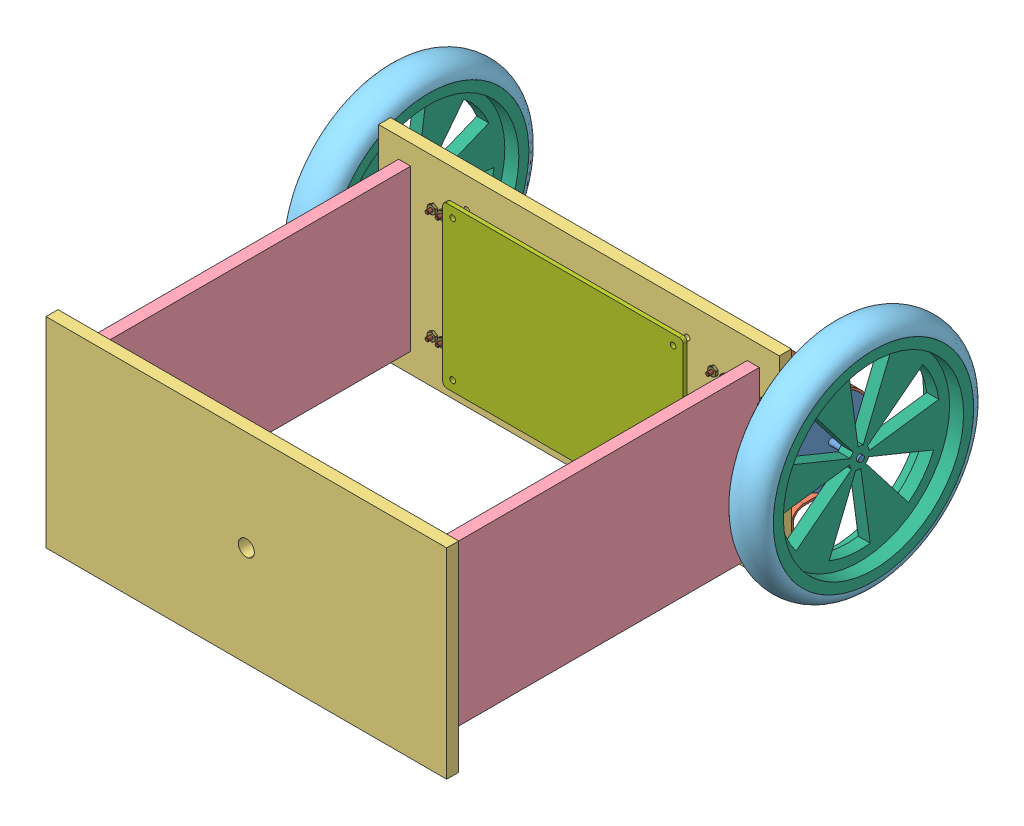
SolidWorks assembly marvin1, configuration Défaut. Lengths in mm.
Overall size (242 114 249).
83 component instances, 12 part files, 144 mates.
Components (placement in the parent):
- moteur-fixation-1: moteur-fixation [Défaut] at (-12.3329 9.7306 0.5) size (75 60.01 41)
  - moteur40-60-1: moteur40-60 [Défaut] at (-38.9333 4.3561 110) size (75 40 40)
  - fixationMoteur40-2-2: fixationMoteur40-2 [Défaut] at (21.0667 4.3561 110) x (0 1 0) z (0 0 1) size (60.01 10 41)
  - fixationMoteur40-2-3: fixationMoteur40-2 [Défaut] at (-3.9333 4.3561 110) x (0 1 0) z (0 0 1) size (60.01 10 41)
  - fixationMoteur40-2-4: fixationMoteur40-2 [Défaut] at (-28.9333 4.3561 110) x (0 1 0) z (0 0 1) size (60.01 10 41)
- plaque200-100-6-1: plaque200-100-6 [Défaut] at (-151.2662 -35.9099 130.5) x (0 0 1) z (0 1 0) size (6 200 100)
- moteur-fixation-2: moteur-fixation [Défaut] at (-170.1995 18.4428 0.5) x (-1 0 0) z (0 0 1) size (75 60.01 41)
  - moteur40-60-1: moteur40-60 [Défaut] at (-38.9333 4.3561 110) size (75 40 40)
  - fixationMoteur40-2-2: fixationMoteur40-2 [Défaut] at (21.0667 4.3561 110) x (0 1 0) z (0 0 1) size (60.01 10 41)
  - fixationMoteur40-2-3: fixationMoteur40-2 [Défaut] at (-3.9333 4.3561 110) x (0 1 0) z (0 0 1) size (60.01 10 41)
  - fixationMoteur40-2-4: fixationMoteur40-2 [Défaut] at (-28.9333 4.3561 110) x (0 1 0) z (0 0 1) size (60.01 10 41)
- plaque160-80-6-1: plaque160-80-6 [Défaut] at (-7.2662 -25.9099 296.5) x (1 0 0) z (0 1 0) size (6 160 80)
- roue200-2-1: roue200-2 [Défaut] at (133.7338 9.4583 108.5273) x (0 0 1) z (-1 0 0) size (114 114 20)
  - pneu-200-2-1: pneu-200-2 [Défaut] at (1.9727 4.6283 114) size (114 114 20)
  - jante10-2-1: jante10-2 [Défaut] at (1.9727 4.6283 104) size (100 100 20)
- roue200-2-2: roue200-2 [Défaut] at (-316.2662 9.4583 112.4727) x (0 0 -1) z (1 0 0) size (114 114 20)
  - pneu-200-2-1: pneu-200-2 [Défaut] at (1.9727 4.6283 114) size (114 114 20)
  - jante10-2-1: jante10-2 [Défaut] at (1.9727 4.6283 104) size (100 100 20)
- plaque160-80-6-2: plaque160-80-6 [Défaut] at (-181.2662 -25.9099 296.5) x (1 0 0) z (0 1 0) size (6 160 80)
- plaque200-100-6-2: plaque200-100-6 [Défaut] at (-31.2662 64.0901 296.5) x (0 0 1) z (0 -1 0) size (6 200 100)
- carte-1: carte [Défaut] at (-152.2662 -25.9099 141.5) size (120 80 2)
- butee15-15-1: butee15-15 [Défaut] at (-51.2662 9.0901 130.5) x (0 0 -1) z (0 1 0) size (16 16 10)
- butee15-15-2: butee15-15 [Défaut] at (-131.2662 19.0901 130.5) x (0 0 -1) z (0 -1 0) size (16 16 10)
- socket head cap screw_am-1: socket head cap screw_am [B18.3.1M - 2 x 0.4 x 10 Hex SHCS -- 10NHX] at (-125.7318 11.5901 128.5) x (0 0 1) z (-1 0 0) size (12 3.8 3.8)
- socket head cap screw_am-2: socket head cap screw_am [B18.3.1M - 2 x 0.4 x 10 Hex SHCS -- 10NHX] at (-125.7318 16.5901 128.5) x (0 0 1) z (-1 0 0) size (12 3.8 3.8)
- socket head cap screw_am-3: socket head cap screw_am [B18.3.1M - 2 x 0.4 x 10 Hex SHCS -- 10NHX] at (-118.7318 11.5901 128.5) x (0 0 1) z (-1 0 0) size (12 3.8 3.8)
- socket head cap screw_am-4: socket head cap screw_am [B18.3.1M - 2 x 0.4 x 10 Hex SHCS -- 10NHX] at (-118.7318 16.5901 128.5) x (0 0 1) z (-1 0 0) size (12 3.8 3.8)
- hex nut style 1_am-1: hex nut style 1_am [B18.2.4.1M - Hex nut, Style 1,  M2 x 0.4 --D-N] at (-125.7318 11.5901 138.1) size (4 4.62 1.6)
- hex nut style 1_am-2: hex nut style 1_am [B18.2.4.1M - Hex nut, Style 1,  M2 x 0.4 --D-N] at (-118.7318 11.5901 138.1) size (4 4.62 1.6)
- hex nut style 1_am-3: hex nut style 1_am [B18.2.4.1M - Hex nut, Style 1,  M2 x 0.4 --D-N] at (-118.7318 16.5901 138.1) size (4 4.62 1.6)
- hex nut style 1_am-4: hex nut style 1_am [B18.2.4.1M - Hex nut, Style 1,  M2 x 0.4 --D-N] at (-125.7318 16.5901 138.1) size (4 4.62 1.6)
- socket head cap screw_am-5: socket head cap screw_am [B18.3.1M - 2 x 0.4 x 10 Hex SHCS -- 10NHX] at (-63.8006 16.5901 128.5) x (0 0 1) z (-1 0 0) size (12 3.8 3.8)
- socket head cap screw_am-6: socket head cap screw_am [B18.3.1M - 2 x 0.4 x 10 Hex SHCS -- 10NHX] at (-56.8006 16.5901 128.5) x (0 0 1) z (-1 0 0) size (12 3.8 3.8)
- socket head cap screw_am-7: socket head cap screw_am [B18.3.1M - 2 x 0.4 x 10 Hex SHCS -- 10NHX] at (-56.8006 11.6838 128.5) x (0 0 1) z (-1 0 0) size (12 3.8 3.8)
- socket head cap screw_am-8: socket head cap screw_am [B18.3.1M - 2 x 0.4 x 10 Hex SHCS -- 10NHX] at (-63.8006 11.5901 128.5) x (0 0 1) z (-1 0 0) size (12 3.8 3.8)
- hex nut style 1_am-5: hex nut style 1_am [B18.2.4.1M - Hex nut, Style 1,  M2 x 0.4 --D-N] at (-63.8006 16.5901 138.1) size (4 4.62 1.6)
- hex nut style 1_am-6: hex nut style 1_am [B18.2.4.1M - Hex nut, Style 1,  M2 x 0.4 --D-N] at (-56.8006 16.5901 138.1) size (4 4.62 1.6)
- hex nut style 1_am-7: hex nut style 1_am [B18.2.4.1M - Hex nut, Style 1,  M2 x 0.4 --D-N] at (-56.8006 11.6838 138.1) size (4 4.62 1.6)
- hex nut style 1_am-8: hex nut style 1_am [B18.2.4.1M - Hex nut, Style 1,  M2 x 0.4 --D-N] at (-63.8006 11.5901 138.1) size (4 4.62 1.6)
- socket head cap screw_ai-3: socket head cap screw_ai [HX-SHCS 0.073-72x0.375x0.375-N] at (-23.7662 -13.4168 128.6458) x (0 0 1) z (-1 0 0) size (11.38 3 3)
- socket head cap screw_ai-4: socket head cap screw_ai [HX-SHCS 0.073-72x0.375x0.375-N] at (-18.7662 -13.4168 128.6458) x (0 0 1) z (-1 0 0) size (11.38 3 3)
- socket head cap screw_ai-5: socket head cap screw_ai [HX-SHCS 0.073-72x0.375x0.375-N] at (1.2338 -13.4168 128.6458) x (0 0 1) z (-1 0 0) size (11.38 3 3)
- socket head cap screw_ai-6: socket head cap screw_ai [HX-SHCS 0.073-72x0.375x0.375-N] at (6.2338 -13.4168 128.6458) x (0 0 1) z (-1 0 0) size (11.38 3 3)
- socket head cap screw_ai-7: socket head cap screw_ai [HX-SHCS 0.073-72x0.375x0.375-N] at (6.9751 40.8664 128.6458) x (0 0 1) z (-1 0 0) size (11.38 3 3)
- socket head cap screw_ai-8: socket head cap screw_ai [HX-SHCS 0.073-72x0.375x0.375-N] at (1.9751 40.8664 128.6458) x (0 0 1) z (-1 0 0) size (11.38 3 3)
- socket head cap screw_ai-9: socket head cap screw_ai [HX-SHCS 0.073-72x0.375x0.375-N] at (-17.8435 41.1189 128.6458) x (0 0 1) z (-1 0 0) size (11.38 3 3)
- socket head cap screw_ai-10: socket head cap screw_ai [HX-SHCS 0.073-72x0.375x0.375-N] at (-23.7662 41.5901 128.6458) x (0 0 1) z (-1 0 0) size (11.38 3 3)
- socket head cap screw_ai-11: socket head cap screw_ai [HX-SHCS 0.073-72x0.375x0.375-N] at (-42.8435 41.1189 128.6458) x (0 0 1) z (-1 0 0) size (11.38 3 3)
- socket head cap screw_ai-12: socket head cap screw_ai [HX-SHCS 0.073-72x0.375x0.375-N] at (-47.7301 41.5901 128.6458) x (0 0 1) z (-1 0 0) size (11.38 3 3)
- socket head cap screw_ai-13: socket head cap screw_ai [HX-SHCS 0.073-72x0.375x0.375-N] at (-132.8435 41.1189 128.6458) x (0 0 1) z (-1 0 0) size (11.38 3 3)
- socket head cap screw_ai-14: socket head cap screw_ai [HX-SHCS 0.073-72x0.375x0.375-N] at (-137.8435 41.1189 128.6458) x (0 0 1) z (-1 0 0) size (11.38 3 3)
- socket head cap screw_ai-15: socket head cap screw_ai [HX-SHCS 0.073-72x0.375x0.375-N] at (-158.7662 41.5901 128.6458) x (0 0 1) z (-1 0 0) size (11.38 3 3)
- socket head cap screw_ai-16: socket head cap screw_ai [HX-SHCS 0.073-72x0.375x0.375-N] at (-163.7662 41.5901 128.6458) x (0 0 1) z (-1 0 0) size (11.38 3 3)
- socket head cap screw_ai-17: socket head cap screw_ai [HX-SHCS 0.073-72x0.375x0.375-N] at (-183.7662 41.5901 128.6458) x (0 0 1) z (-1 0 0) size (11.38 3 3)
- socket head cap screw_ai-18: socket head cap screw_ai [HX-SHCS 0.073-72x0.375x0.375-N] at (-188.7662 41.5901 128.6458) x (0 0 1) z (-1 0 0) size (11.38 3 3)
- socket head cap screw_ai-19: socket head cap screw_ai [HX-SHCS 0.073-72x0.375x0.375-N] at (-188.7662 -13.4168 128.6458) x (0 0 1) z (-1 0 0) size (11.38 3 3)
- socket head cap screw_ai-20: socket head cap screw_ai [HX-SHCS 0.073-72x0.375x0.375-N] at (-183.7662 -13.4168 128.6458) x (0 0 1) z (-1 0 0) size (11.38 3 3)
- socket head cap screw_ai-21: socket head cap screw_ai [HX-SHCS 0.073-72x0.375x0.375-N] at (-163.7662 -13.4168 128.6458) x (0 0 1) z (-1 0 0) size (11.38 3 3)
- socket head cap screw_ai-22: socket head cap screw_ai [HX-SHCS 0.073-72x0.375x0.375-N] at (-158.7662 -13.4168 128.6458) x (0 0 1) z (-1 0 0) size (11.38 3 3)
- socket head cap screw_ai-23: socket head cap screw_ai [HX-SHCS 0.073-72x0.375x0.375-N] at (-138.7662 -13.4168 128.6458) x (0 0 1) z (-1 0 0) size (11.38 3 3)
- socket head cap screw_ai-24: socket head cap screw_ai [HX-SHCS 0.073-72x0.375x0.375-N] at (-133.7662 -13.4168 128.6458) x (0 0 1) z (-1 0 0) size (11.38 3 3)
- machine screw nut hex_ai-1: machine screw nut hex_ai [MSHXNUT 0.073-72-S-N] at (-23.7662 -13.4168 137.77) size (3.96 4.58 1.27)
- machine screw nut hex_ai-2: machine screw nut hex_ai [MSHXNUT 0.073-72-S-N] at (-18.7662 -13.4168 137.77) size (3.96 4.58 1.27)
- machine screw nut hex_ai-3: machine screw nut hex_ai [MSHXNUT 0.073-72-S-N] at (1.2338 -13.4168 137.77) size (3.96 4.58 1.27)
- machine screw nut hex_ai-4: machine screw nut hex_ai [MSHXNUT 0.073-72-S-N] at (6.2338 -13.4168 137.77) size (3.96 4.58 1.27)
- machine screw nut hex_ai-5: machine screw nut hex_ai [MSHXNUT 0.073-72-S-N] at (6.9751 40.8664 137.77) size (3.96 4.58 1.27)
- machine screw nut hex_ai-6: machine screw nut hex_ai [MSHXNUT 0.073-72-S-N] at (1.9751 40.8664 137.77) size (3.96 4.58 1.27)
- machine screw nut hex_ai-7: machine screw nut hex_ai [MSHXNUT 0.073-72-S-N] at (-17.8435 41.1189 137.77) size (3.96 4.58 1.27)
- machine screw nut hex_ai-8: machine screw nut hex_ai [MSHXNUT 0.073-72-S-N] at (-23.7662 41.5901 137.77) size (3.96 4.58 1.27)
- machine screw nut hex_ai-9: machine screw nut hex_ai [MSHXNUT 0.073-72-S-N] at (-42.8435 41.1189 137.77) size (3.96 4.58 1.27)
- machine screw nut hex_ai-10: machine screw nut hex_ai [MSHXNUT 0.073-72-S-N] at (-47.7301 41.5901 137.77) size (3.96 4.58 1.27)
- machine screw nut hex_ai-11: machine screw nut hex_ai [MSHXNUT 0.073-72-S-N] at (-132.8435 41.1189 137.77) size (3.96 4.58 1.27)
- machine screw nut hex_ai-12: machine screw nut hex_ai [MSHXNUT 0.073-72-S-N] at (-137.8435 41.1189 137.77) size (3.96 4.58 1.27)
- machine screw nut hex_ai-13: machine screw nut hex_ai [MSHXNUT 0.073-72-S-N] at (-158.7662 41.5901 137.77) size (3.96 4.58 1.27)
- machine screw nut hex_ai-14: machine screw nut hex_ai [MSHXNUT 0.073-72-S-N] at (-163.7662 41.5901 137.77) size (3.96 4.58 1.27)
- machine screw nut hex_ai-15: machine screw nut hex_ai [MSHXNUT 0.073-72-S-N] at (-183.7662 41.5901 137.77) size (3.96 4.58 1.27)
- machine screw nut hex_ai-16: machine screw nut hex_ai [MSHXNUT 0.073-72-S-N] at (-188.7662 41.5901 137.77) size (3.96 4.58 1.27)
- machine screw nut hex_ai-17: machine screw nut hex_ai [MSHXNUT 0.073-72-S-N] at (-188.7662 -13.4168 137.77) size (3.96 4.58 1.27)
- machine screw nut hex_ai-18: machine screw nut hex_ai [MSHXNUT 0.073-72-S-N] at (-183.7662 -13.4168 137.77) size (3.96 4.58 1.27)
- machine screw nut hex_ai-19: machine screw nut hex_ai [MSHXNUT 0.073-72-S-N] at (-163.7662 -13.4168 137.77) size (3.96 4.58 1.27)
- machine screw nut hex_ai-20: machine screw nut hex_ai [MSHXNUT 0.073-72-S-N] at (-158.7662 -13.4168 137.77) size (3.96 4.58 1.27)
- machine screw nut hex_ai-21: machine screw nut hex_ai [MSHXNUT 0.073-72-S-N] at (-138.7662 -13.4168 137.77) size (3.96 4.58 1.27)
- machine screw nut hex_ai-22: machine screw nut hex_ai [MSHXNUT 0.073-72-S-N] at (-133.7662 -13.4168 137.77) size (3.96 4.58 1.27)
Mates (geometry in assembly coordinates):
- Coïncidente1: coincident: plane of moteur-fixation-1/fixationMoteur40-2-2 through (-1.2662 39.0501 130.5) normal (0 0 1); plane of plaque200-100-6-1 through (8.7338 64.0901 130.5) normal (0 0 -1)
- Coïncidente2: coincident: plane of moteur-fixation-1/fixationMoteur40-2-2 through (8.7338 -12.303 124.2714) normal (1 0 0); plane of plaque200-100-6-1 through (8.7338 64.0901 130.5) normal (1 0 0)
- Distance1: distance = 20 mm: plane of moteur-fixation-1/fixationMoteur40-2-2 through (-1.2662 44.0901 130.5) normal (0 1 0); plane of plaque200-100-6-1 through (-151.2662 64.0901 130.5) normal (0 1 0)
- Coïncidente4: coincident: plane of plaque200-100-6-1 through (-191.2662 64.0901 130.5) normal (-1 0 0); plane of moteur-fixation-2/moteur40-60-1 through (-191.2662 14.0867 110.5) normal (-1 0 0)
- Coïncidente5: coincident: plane of plaque200-100-6-1 through (8.7338 64.0901 130.5) normal (0 0 -1); plane of moteur-fixation-2/fixationMoteur40-2-2 through (-181.2662 39.0501 130.5) normal (0 0 1)
- Distance2: distance = 20 mm: plane of moteur-fixation-2/fixationMoteur40-2-2 through (-181.2662 44.0901 130.5) normal (0 1 0); plane of plaque200-100-6-1 through (-151.2662 64.0901 130.5) normal (0 1 0)
- Coïncidente7: coincident: plane of plaque200-100-6-1 through (8.7338 64.0901 136.5) normal (0 0 1); plane of plaque160-80-6-1 through (-7.2662 54.0901 136.5) normal (0 0 -1)
- Distance3: distance = 10 mm: plane of plaque160-80-6-1 through (-7.2662 54.0901 296.5) normal (0 1 0); plane of plaque200-100-6-1 through (-151.2662 64.0901 130.5) normal (0 1 0)
- Distance5: distance = 10 mm: plane of plaque200-100-6-1 through (8.7338 64.0901 130.5) normal (1 0 0); plane of plaque160-80-6-1 through (-1.2662 54.0901 136.5) normal (1 0 0)
- Coïncidente11: coincident: cylinder of moteur-fixation-1/moteur40-60-1 through (23.7338 14.0867 110.5) axis (-1 0 0) radius 1.5; circle of roue200-2-1/jante10-2-1
- Distance6: distance = 8 mm: plane of roue200-2-1/jante10-2-1 through (16.7338 14.0867 110.5) normal (-1 0 0); plane of moteur-fixation-1/moteur40-60-1 through (8.7338 14.0867 110.5) normal (1 0 0)
- Coïncidente13: coincident: cylinder of moteur-fixation-2/moteur40-60-1 through (-206.2662 14.0867 110.5) axis (1 0 0) radius 1.5; circle of roue200-2-2/jante10-2-1
- Distance7: distance = 8 mm: plane of roue200-2-2/jante10-2-1 through (-199.2662 14.0867 110.5) normal (1 0 0); plane of moteur-fixation-2/moteur40-60-1 through (-191.2662 14.0867 110.5) normal (-1 0 0)
- Coïncidente15: coincident: plane of plaque200-100-6-1 through (8.7338 64.0901 136.5) normal (0 0 1); plane of plaque160-80-6-2 through (-181.2662 54.0901 136.5) normal (0 0 -1)
- Distance8: distance = 10 mm: plane of plaque160-80-6-2 through (-181.2662 54.0901 296.5) normal (0 1 0); plane of plaque200-100-6-1 through (-151.2662 64.0901 130.5) normal (0 1 0)
- Distance9: distance = 10 mm: plane of plaque200-100-6-1 through (-191.2662 64.0901 130.5) normal (-1 0 0); plane of plaque160-80-6-2 through (-181.2662 54.0901 136.5) normal (-1 0 0)
- Coïncidente18: coincident: plane of plaque160-80-6-1 through (-7.2662 54.0901 296.5) normal (0 0 1); plane of plaque200-100-6-2 through (-191.2662 -35.9099 296.5) normal (0 0 -1)
- Coïncidente19: coincident: plane of plaque200-100-6-1 through (-151.2662 -35.9099 130.5) normal (0 -1 0); plane of plaque200-100-6-2 through (-31.2662 -35.9099 296.5) normal (0 -1 0)
- Coïncidente20: coincident: plane of plaque200-100-6-1 through (-191.2662 64.0901 130.5) normal (-1 0 0); plane of plaque200-100-6-2 through (-191.2662 -35.9099 296.5) normal (-1 0 0)
- Distance10: distance = 5 mm: plane of carte-1 through (-152.2662 -25.9099 141.5) normal (0 0 -1); plane of plaque200-100-6-1 through (8.7338 64.0901 136.5) normal (0 0 1)
- Distance11: distance = 23 mm: plane of carte-1 through (-152.2662 -25.9099 143.5) normal (-1 0 0); plane of plaque160-80-6-2 through (-175.2662 54.0901 136.5) normal (1 0 0)
- Distance12: distance = 10 mm: plane of carte-1 through (-152.2662 54.0901 143.5) normal (0 1 0); plane of plaque200-100-6-1 through (-151.2662 64.0901 130.5) normal (0 1 0)
- Coïncidente24: coincident: plane of plaque200-100-6-1 through (8.7338 64.0901 130.5) normal (0 0 -1); plane of butee15-15-1 through (-53.2662 19.0901 130.5) normal (0 0 1)
- Coïncidente25: coincident: plane of moteur-fixation-1/moteur40-60-1 through (-51.2662 14.0867 110.5) normal (-1 0 0); plane of butee15-15-1 through (-51.2662 19.0901 130.5) normal (1 0 0)
- Distance13: distance = 45 mm: plane of butee15-15-1 through (-51.2662 19.0901 130.5) normal (0 1 0); plane of plaque200-100-6-1 through (-151.2662 64.0901 130.5) normal (0 1 0)
- Coïncidente27: coincident: plane of plaque200-100-6-1 through (8.7338 64.0901 130.5) normal (0 0 -1); plane of butee15-15-2 through (-129.2662 9.0901 130.5) normal (0 0 1)
- Coïncidente28: coincident: plane of moteur-fixation-2/moteur40-60-1 through (-131.2662 14.0867 110.5) normal (1 0 0); plane of butee15-15-2 through (-131.2662 9.0901 130.5) normal (-1 0 0)
- Distance14: distance = 45 mm: plane of butee15-15-2 through (-131.2662 9.0901 130.5) normal (0 -1 0); plane of plaque200-100-6-1 through (-151.2662 -35.9099 130.5) normal (0 -1 0)
- Coïncidente42: coincident: plane of plaque200-100-6-1 through (8.7338 64.0901 136.5) normal (0 0 1); plane of hex nut style 1_am-1 through (-129.7318 11.5901 136.5) normal (0 0 -1)
- Coïncidente43: coincident: plane of plaque200-100-6-1 through (8.7338 64.0901 136.5) normal (0 0 1); plane of hex nut style 1_am-2 through (-122.7318 11.5901 136.5) normal (0 0 -1)
- Coïncidente44: coincident: plane of plaque200-100-6-1 through (8.7338 64.0901 136.5) normal (0 0 1); plane of hex nut style 1_am-3 through (-122.7318 16.5901 136.5) normal (0 0 -1)
- Coïncidente45: coincident: plane of plaque200-100-6-1 through (8.7338 64.0901 136.5) normal (0 0 1); plane of hex nut style 1_am-4 through (-129.7318 16.5901 136.5) normal (0 0 -1)
- Coaxiale181: concentric: cylinder of plaque200-100-6-1 through (-63.8006 16.5901 130.5) axis (0 0 -1) radius 1.2; cylinder of socket head cap screw_am-5 through (-63.8006 16.5901 96.75) axis (0 0 -1) radius 1
- Coïncidente461: coincident: plane of plaque200-100-6-1 through (8.7338 64.0901 130.5) normal (0 0 -1); plane of socket head cap screw_am-5 through (-63.8006 18.4901 130.5) normal (0 0 1)
- Coaxiale191: concentric: cylinder of plaque200-100-6-1 through (-56.8006 16.5901 130.5) axis (0 0 -1) radius 1.2; cylinder of socket head cap screw_am-6 through (-56.8006 16.5901 96.75) axis (0 0 -1) radius 1
- Coïncidente471: coincident: plane of plaque200-100-6-1 through (8.7338 64.0901 130.5) normal (0 0 -1); plane of socket head cap screw_am-6 through (-56.8006 18.4901 130.5) normal (0 0 1)
- Coaxiale201: concentric: cylinder of plaque200-100-6-1 through (-56.8006 11.6838 130.5) axis (0 0 -1) radius 1.2; cylinder of socket head cap screw_am-7 through (-56.8006 11.6838 96.75) axis (0 0 -1) radius 1
- Coïncidente481: coincident: plane of plaque200-100-6-1 through (8.7338 64.0901 130.5) normal (0 0 -1); plane of socket head cap screw_am-7 through (-56.8006 13.5838 130.5) normal (0 0 1)
- Coaxiale211: concentric: cylinder of plaque200-100-6-1 through (-63.8006 11.5901 130.5) axis (0 0 -1) radius 1.2; cylinder of socket head cap screw_am-8 through (-63.8006 11.5901 96.75) axis (0 0 -1) radius 1
- Coïncidente491: coincident: plane of plaque200-100-6-1 through (8.7338 64.0901 130.5) normal (0 0 -1); plane of socket head cap screw_am-8 through (-63.8006 13.4901 130.5) normal (0 0 1)
- Coaxiale22: concentric: cylinder of socket head cap screw_am-5 through (-63.8006 16.5901 96.75) axis (0 0 -1) radius 1; cylinder of hex nut style 1_am-5 through (-63.8006 16.5901 113.0625) axis (0 0 1) radius 1
- Coïncidente50: coincident: plane of plaque200-100-6-1 through (8.7338 64.0901 136.5) normal (0 0 1); plane of hex nut style 1_am-5 through (-67.8006 16.5901 136.5) normal (0 0 -1)
- Coaxiale23: concentric: cylinder of socket head cap screw_am-6 through (-56.8006 16.5901 96.75) axis (0 0 -1) radius 1; cylinder of hex nut style 1_am-6 through (-56.8006 16.5901 113.0625) axis (0 0 1) radius 1
- Coïncidente51: coincident: plane of plaque200-100-6-1 through (8.7338 64.0901 136.5) normal (0 0 1); plane of hex nut style 1_am-6 through (-60.8006 16.5901 136.5) normal (0 0 -1)
- Coaxiale24: concentric: cylinder of socket head cap screw_am-7 through (-56.8006 11.6838 96.75) axis (0 0 -1) radius 1; cylinder of hex nut style 1_am-7 through (-56.8006 11.6838 113.0625) axis (0 0 1) radius 1
- Coïncidente52: coincident: plane of plaque200-100-6-1 through (8.7338 64.0901 136.5) normal (0 0 1); plane of hex nut style 1_am-7 through (-60.8006 11.6838 136.5) normal (0 0 -1)
- Coaxiale25: concentric: cylinder of socket head cap screw_am-8 through (-63.8006 11.5901 96.75) axis (0 0 -1) radius 1; cylinder of hex nut style 1_am-8 through (-63.8006 11.5901 113.0625) axis (0 0 1) radius 1
- Coïncidente53: coincident: plane of plaque200-100-6-1 through (8.7338 64.0901 136.5) normal (0 0 1); plane of hex nut style 1_am-8 through (-67.8006 11.5901 136.5) normal (0 0 -1)
- Coaxiale301: concentric: cylinder of plaque200-100-6-1 through (-125.7318 11.5901 130.5) axis (0 0 -1) radius 1.2; cylinder of socket head cap screw_am-1 through (-125.7318 11.5901 96.75) axis (0 0 -1) radius 1
- Coïncidente581: coincident: plane of plaque200-100-6-1 through (8.7338 64.0901 130.5) normal (0 0 -1); plane of socket head cap screw_am-1 through (-125.7318 13.4901 130.5) normal (0 0 1)
- Coaxiale311: concentric: cylinder of plaque200-100-6-1 through (-118.7318 11.5901 130.5) axis (0 0 -1) radius 1.2; cylinder of socket head cap screw_am-3 through (-118.7318 11.5901 96.75) axis (0 0 -1) radius 1
- Coïncidente591: coincident: plane of plaque200-100-6-1 through (8.7338 64.0901 130.5) normal (0 0 -1); plane of socket head cap screw_am-3 through (-118.7318 13.4901 130.5) normal (0 0 1)
- Coaxiale321: concentric: cylinder of plaque200-100-6-1 through (-118.7318 16.5901 130.5) axis (0 0 -1) radius 1.2; cylinder of socket head cap screw_am-4 through (-118.7318 16.5901 96.75) axis (0 0 -1) radius 1
- Coïncidente601: coincident: plane of plaque200-100-6-1 through (8.7338 64.0901 130.5) normal (0 0 -1); plane of socket head cap screw_am-4 through (-118.7318 18.4901 130.5) normal (0 0 1)
- Coaxiale331: concentric: cylinder of plaque200-100-6-1 through (-125.7318 16.5901 130.5) axis (0 0 -1) radius 1.2; cylinder of socket head cap screw_am-2 through (-125.7318 16.5901 96.75) axis (0 0 -1) radius 1
- Coïncidente611: coincident: plane of plaque200-100-6-1 through (8.7338 64.0901 130.5) normal (0 0 -1); plane of socket head cap screw_am-2 through (-125.7318 18.4901 130.5) normal (0 0 1)
- Coaxiale361: concentric: cylinder of plaque200-100-6-1 through (-23.7662 -13.4168 130.5) axis (0 0 -1) radius 1.0287; cylinder of socket head cap screw_ai-3 through (-23.7662 -13.4168 96.8958) axis (0 0 -1) radius 0.9271
- Coïncidente641: coincident: plane of plaque200-100-6-1 through (8.7338 64.0901 130.5) normal (0 0 -1); plane of socket head cap screw_ai-3 through (-23.7662 -11.9182 130.5) normal (0 0 1)
- Coaxiale371: concentric: cylinder of plaque200-100-6-1 through (-18.7662 -13.4168 130.5) axis (0 0 -1) radius 1.0287; cylinder of socket head cap screw_ai-4 through (-18.7662 -13.4168 96.8958) axis (0 0 -1) radius 0.9271
- Coïncidente651: coincident: plane of plaque200-100-6-1 through (8.7338 64.0901 130.5) normal (0 0 -1); plane of socket head cap screw_ai-4 through (-18.7662 -11.9182 130.5) normal (0 0 1)
- Coaxiale381: concentric: cylinder of plaque200-100-6-1 through (1.2338 -13.4168 130.5) axis (0 0 -1) radius 1.0287; cylinder of socket head cap screw_ai-5 through (1.2338 -13.4168 96.8958) axis (0 0 -1) radius 0.9271
- Coïncidente661: coincident: plane of plaque200-100-6-1 through (8.7338 64.0901 130.5) normal (0 0 -1); plane of socket head cap screw_ai-5 through (1.2338 -11.9182 130.5) normal (0 0 1)
- Coaxiale391: concentric: cylinder of plaque200-100-6-1 through (6.2338 -13.4168 130.5) axis (0 0 -1) radius 1.0287; cylinder of socket head cap screw_ai-6 through (6.2338 -13.4168 96.8958) axis (0 0 -1) radius 0.9271
- Coïncidente671: coincident: plane of plaque200-100-6-1 through (8.7338 64.0901 130.5) normal (0 0 -1); plane of socket head cap screw_ai-6 through (6.2338 -11.9182 130.5) normal (0 0 1)
- Coaxiale401: concentric: cylinder of plaque200-100-6-1 through (6.9751 40.8664 130.5) axis (0 0 -1) radius 1.0287; cylinder of socket head cap screw_ai-7 through (6.9751 40.8664 96.8958) axis (0 0 -1) radius 0.9271
- Coïncidente681: coincident: plane of plaque200-100-6-1 through (8.7338 64.0901 130.5) normal (0 0 -1); plane of socket head cap screw_ai-7 through (6.9751 42.365 130.5) normal (0 0 1)
- Coaxiale411: concentric: cylinder of plaque200-100-6-1 through (1.9751 40.8664 130.5) axis (0 0 -1) radius 1.0287; cylinder of socket head cap screw_ai-8 through (1.9751 40.8664 96.8958) axis (0 0 -1) radius 0.9271
- Coïncidente691: coincident: plane of plaque200-100-6-1 through (8.7338 64.0901 130.5) normal (0 0 -1); plane of socket head cap screw_ai-8 through (1.9751 42.365 130.5) normal (0 0 1)
- Coaxiale421: concentric: cylinder of plaque200-100-6-1 through (-17.8435 41.1189 130.5) axis (0 0 -1) radius 1.0287; cylinder of socket head cap screw_ai-9 through (-17.8435 41.1189 96.8958) axis (0 0 -1) radius 0.9271
- Coïncidente701: coincident: plane of plaque200-100-6-1 through (8.7338 64.0901 130.5) normal (0 0 -1); plane of socket head cap screw_ai-9 through (-17.8435 42.6175 130.5) normal (0 0 1)
- Coaxiale431: concentric: cylinder of plaque200-100-6-1 through (-23.7662 41.5901 130.5) axis (0 0 -1) radius 1.0287; cylinder of socket head cap screw_ai-10 through (-23.7662 41.5901 96.8958) axis (0 0 -1) radius 0.9271
- Coïncidente711: coincident: plane of plaque200-100-6-1 through (8.7338 64.0901 130.5) normal (0 0 -1); plane of socket head cap screw_ai-10 through (-23.7662 43.0887 130.5) normal (0 0 1)
- Coaxiale441: concentric: cylinder of plaque200-100-6-1 through (-42.8435 41.1189 130.5) axis (0 0 -1) radius 1.0287; cylinder of socket head cap screw_ai-11 through (-42.8435 41.1189 96.8958) axis (0 0 -1) radius 0.9271
- Coïncidente721: coincident: plane of plaque200-100-6-1 through (8.7338 64.0901 130.5) normal (0 0 -1); plane of socket head cap screw_ai-11 through (-42.8435 42.6175 130.5) normal (0 0 1)
- Coaxiale451: concentric: cylinder of plaque200-100-6-1 through (-47.7301 41.5901 130.5) axis (0 0 -1) radius 1.0287; cylinder of socket head cap screw_ai-12 through (-47.7301 41.5901 96.8958) axis (0 0 -1) radius 0.9271
- Coïncidente731: coincident: plane of plaque200-100-6-1 through (8.7338 64.0901 130.5) normal (0 0 -1); plane of socket head cap screw_ai-12 through (-47.7301 43.0887 130.5) normal (0 0 1)
- Coaxiale461: concentric: cylinder of plaque200-100-6-1 through (-132.8435 41.1189 130.5) axis (0 0 -1) radius 1.0287; cylinder of socket head cap screw_ai-13 through (-132.8435 41.1189 96.8958) axis (0 0 -1) radius 0.9271
- Coïncidente741: coincident: plane of plaque200-100-6-1 through (8.7338 64.0901 130.5) normal (0 0 -1); plane of socket head cap screw_ai-13 through (-132.8435 42.6175 130.5) normal (0 0 1)
- Coaxiale471: concentric: cylinder of plaque200-100-6-1 through (-137.8435 41.1189 130.5) axis (0 0 -1) radius 1.0287; cylinder of socket head cap screw_ai-14 through (-137.8435 41.1189 96.8958) axis (0 0 -1) radius 0.9271
- Coïncidente751: coincident: plane of plaque200-100-6-1 through (8.7338 64.0901 130.5) normal (0 0 -1); plane of socket head cap screw_ai-14 through (-137.8435 42.6175 130.5) normal (0 0 1)
- Coaxiale481: concentric: cylinder of plaque200-100-6-1 through (-158.7662 41.5901 130.5) axis (0 0 -1) radius 1.0287; cylinder of socket head cap screw_ai-15 through (-158.7662 41.5901 96.8958) axis (0 0 -1) radius 0.9271
- Coïncidente761: coincident: plane of plaque200-100-6-1 through (8.7338 64.0901 130.5) normal (0 0 -1); plane of socket head cap screw_ai-15 through (-158.7662 43.0887 130.5) normal (0 0 1)
- Coaxiale491: concentric: cylinder of plaque200-100-6-1 through (-163.7662 41.5901 130.5) axis (0 0 -1) radius 1.0287; cylinder of socket head cap screw_ai-16 through (-163.7662 41.5901 96.8958) axis (0 0 -1) radius 0.9271
- Coïncidente771: coincident: plane of plaque200-100-6-1 through (8.7338 64.0901 130.5) normal (0 0 -1); plane of socket head cap screw_ai-16 through (-163.7662 43.0887 130.5) normal (0 0 1)
- Coaxiale501: concentric: cylinder of plaque200-100-6-1 through (-183.7662 41.5901 130.5) axis (0 0 -1) radius 1.0287; cylinder of socket head cap screw_ai-17 through (-183.7662 41.5901 96.8958) axis (0 0 -1) radius 0.9271
- Coïncidente781: coincident: plane of plaque200-100-6-1 through (8.7338 64.0901 130.5) normal (0 0 -1); plane of socket head cap screw_ai-17 through (-183.7662 43.0887 130.5) normal (0 0 1)
- Coaxiale511: concentric: cylinder of plaque200-100-6-1 through (-188.7662 41.5901 130.5) axis (0 0 -1) radius 1.0287; cylinder of socket head cap screw_ai-18 through (-188.7662 41.5901 96.8958) axis (0 0 -1) radius 0.9271
- Coïncidente791: coincident: plane of plaque200-100-6-1 through (8.7338 64.0901 130.5) normal (0 0 -1); plane of socket head cap screw_ai-18 through (-188.7662 43.0887 130.5) normal (0 0 1)
- Coaxiale521: concentric: cylinder of plaque200-100-6-1 through (-188.7662 -13.4168 130.5) axis (0 0 -1) radius 1.0287; cylinder of socket head cap screw_ai-19 through (-188.7662 -13.4168 96.8958) axis (0 0 -1) radius 0.9271
- Coïncidente801: coincident: plane of plaque200-100-6-1 through (8.7338 64.0901 130.5) normal (0 0 -1); plane of socket head cap screw_ai-19 through (-188.7662 -11.9182 130.5) normal (0 0 1)
- Coaxiale531: concentric: cylinder of plaque200-100-6-1 through (-183.7662 -13.4168 130.5) axis (0 0 -1) radius 1.0287; cylinder of socket head cap screw_ai-20 through (-183.7662 -13.4168 96.8958) axis (0 0 -1) radius 0.9271
- Coïncidente811: coincident: plane of plaque200-100-6-1 through (8.7338 64.0901 130.5) normal (0 0 -1); plane of socket head cap screw_ai-20 through (-183.7662 -11.9182 130.5) normal (0 0 1)
- Coaxiale541: concentric: cylinder of plaque200-100-6-1 through (-163.7662 -13.4168 130.5) axis (0 0 -1) radius 1.0287; cylinder of socket head cap screw_ai-21 through (-163.7662 -13.4168 96.8958) axis (0 0 -1) radius 0.9271
- Coïncidente821: coincident: plane of plaque200-100-6-1 through (8.7338 64.0901 130.5) normal (0 0 -1); plane of socket head cap screw_ai-21 through (-163.7662 -11.9182 130.5) normal (0 0 1)
- Coaxiale551: concentric: cylinder of plaque200-100-6-1 through (-158.7662 -13.4168 130.5) axis (0 0 -1) radius 1.0287; cylinder of socket head cap screw_ai-22 through (-158.7662 -13.4168 96.8958) axis (0 0 -1) radius 0.9271
- Coïncidente831: coincident: plane of plaque200-100-6-1 through (8.7338 64.0901 130.5) normal (0 0 -1); plane of socket head cap screw_ai-22 through (-158.7662 -11.9182 130.5) normal (0 0 1)
- Coaxiale561: concentric: cylinder of plaque200-100-6-1 through (-138.7662 -13.4168 130.5) axis (0 0 -1) radius 1.0287; cylinder of socket head cap screw_ai-23 through (-138.7662 -13.4168 96.8958) axis (0 0 -1) radius 0.9271
- Coïncidente841: coincident: plane of plaque200-100-6-1 through (8.7338 64.0901 130.5) normal (0 0 -1); plane of socket head cap screw_ai-23 through (-138.7662 -11.9182 130.5) normal (0 0 1)
- Coaxiale571: concentric: cylinder of plaque200-100-6-1 through (-133.7662 -13.4168 130.5) axis (0 0 -1) radius 1.0287; cylinder of socket head cap screw_ai-24 through (-133.7662 -13.4168 96.8958) axis (0 0 -1) radius 0.9271
- Coïncidente851: coincident: plane of plaque200-100-6-1 through (8.7338 64.0901 130.5) normal (0 0 -1); plane of socket head cap screw_ai-24 through (-133.7662 -11.9182 130.5) normal (0 0 1)
- Coaxiale58: concentric: cylinder of socket head cap screw_ai-3 through (-23.7662 -13.4168 96.8958) axis (0 0 -1) radius 0.9271; cylinder of machine screw nut hex_ai-1 through (-23.7662 -13.4168 112.7325) axis (0 0 1) radius 0.9271
- Coïncidente86: coincident: plane of plaque200-100-6-1 through (8.7338 64.0901 136.5) normal (0 0 1); plane of machine screw nut hex_ai-1 through (-23.7662 -11.1291 136.5) normal (0 0 -1)
- Coaxiale59: concentric: cylinder of socket head cap screw_ai-4 through (-18.7662 -13.4168 96.8958) axis (0 0 -1) radius 0.9271; cylinder of machine screw nut hex_ai-2 through (-18.7662 -13.4168 112.7325) axis (0 0 1) radius 0.9271
- Coïncidente87: coincident: plane of plaque200-100-6-1 through (8.7338 64.0901 136.5) normal (0 0 1); plane of machine screw nut hex_ai-2 through (-18.7662 -11.1291 136.5) normal (0 0 -1)
- Coaxiale60: concentric: cylinder of socket head cap screw_ai-5 through (1.2338 -13.4168 96.8958) axis (0 0 -1) radius 0.9271; cylinder of machine screw nut hex_ai-3 through (1.2338 -13.4168 112.7325) axis (0 0 1) radius 0.9271
- Coïncidente88: coincident: plane of plaque200-100-6-1 through (8.7338 64.0901 136.5) normal (0 0 1); plane of machine screw nut hex_ai-3 through (1.2338 -11.1291 136.5) normal (0 0 -1)
- Coaxiale61: concentric: cylinder of socket head cap screw_ai-6 through (6.2338 -13.4168 96.8958) axis (0 0 -1) radius 0.9271; cylinder of machine screw nut hex_ai-4 through (6.2338 -13.4168 112.7325) axis (0 0 1) radius 0.9271
- Coïncidente89: coincident: plane of plaque200-100-6-1 through (8.7338 64.0901 136.5) normal (0 0 1); plane of machine screw nut hex_ai-4 through (6.2338 -11.1291 136.5) normal (0 0 -1)
- Coaxiale62: concentric: cylinder of socket head cap screw_ai-7 through (6.9751 40.8664 96.8958) axis (0 0 -1) radius 0.9271; cylinder of machine screw nut hex_ai-5 through (6.9751 40.8664 112.7325) axis (0 0 1) radius 0.9271
- Coïncidente90: coincident: plane of plaque200-100-6-1 through (8.7338 64.0901 136.5) normal (0 0 1); plane of machine screw nut hex_ai-5 through (6.9751 43.1541 136.5) normal (0 0 -1)
- Coaxiale63: concentric: cylinder of socket head cap screw_ai-8 through (1.9751 40.8664 96.8958) axis (0 0 -1) radius 0.9271; cylinder of machine screw nut hex_ai-6 through (1.9751 40.8664 112.7325) axis (0 0 1) radius 0.9271
- Coïncidente91: coincident: plane of plaque200-100-6-1 through (8.7338 64.0901 136.5) normal (0 0 1); plane of machine screw nut hex_ai-6 through (1.9751 43.1541 136.5) normal (0 0 -1)
- Coaxiale64: concentric: cylinder of socket head cap screw_ai-9 through (-17.8435 41.1189 96.8958) axis (0 0 -1) radius 0.9271; cylinder of machine screw nut hex_ai-7 through (-17.8435 41.1189 112.7325) axis (0 0 1) radius 0.9271
- Coïncidente92: coincident: plane of plaque200-100-6-1 through (8.7338 64.0901 136.5) normal (0 0 1); plane of machine screw nut hex_ai-7 through (-17.8435 43.4066 136.5) normal (0 0 -1)
- Coaxiale65: concentric: cylinder of socket head cap screw_ai-10 through (-23.7662 41.5901 96.8958) axis (0 0 -1) radius 0.9271; cylinder of machine screw nut hex_ai-8 through (-23.7662 41.5901 112.7325) axis (0 0 1) radius 0.9271
- Coïncidente93: coincident: plane of plaque200-100-6-1 through (8.7338 64.0901 136.5) normal (0 0 1); plane of machine screw nut hex_ai-8 through (-23.7662 43.8778 136.5) normal (0 0 -1)
- Coaxiale66: concentric: cylinder of socket head cap screw_ai-11 through (-42.8435 41.1189 96.8958) axis (0 0 -1) radius 0.9271; cylinder of machine screw nut hex_ai-9 through (-42.8435 41.1189 112.7325) axis (0 0 1) radius 0.9271
- Coïncidente94: coincident: plane of plaque200-100-6-1 through (8.7338 64.0901 136.5) normal (0 0 1); plane of machine screw nut hex_ai-9 through (-42.8435 43.4066 136.5) normal (0 0 -1)
- Coaxiale67: concentric: cylinder of socket head cap screw_ai-12 through (-47.7301 41.5901 96.8958) axis (0 0 -1) radius 0.9271; cylinder of machine screw nut hex_ai-10 through (-47.7301 41.5901 112.7325) axis (0 0 1) radius 0.9271
- Coïncidente95: coincident: plane of plaque200-100-6-1 through (8.7338 64.0901 136.5) normal (0 0 1); plane of machine screw nut hex_ai-10 through (-47.7301 43.8778 136.5) normal (0 0 -1)
- Coaxiale68: concentric: cylinder of socket head cap screw_ai-13 through (-132.8435 41.1189 96.8958) axis (0 0 -1) radius 0.9271; cylinder of machine screw nut hex_ai-11 through (-132.8435 41.1189 112.7325) axis (0 0 1) radius 0.9271
- Coïncidente96: coincident: plane of plaque200-100-6-1 through (8.7338 64.0901 136.5) normal (0 0 1); plane of machine screw nut hex_ai-11 through (-132.8435 43.4066 136.5) normal (0 0 -1)
- Coaxiale69: concentric: cylinder of socket head cap screw_ai-14 through (-137.8435 41.1189 96.8958) axis (0 0 -1) radius 0.9271; cylinder of machine screw nut hex_ai-12 through (-137.8435 41.1189 112.7325) axis (0 0 1) radius 0.9271
- Coïncidente97: coincident: plane of plaque200-100-6-1 through (8.7338 64.0901 136.5) normal (0 0 1); plane of machine screw nut hex_ai-12 through (-137.8435 43.4066 136.5) normal (0 0 -1)
- Coaxiale70: concentric: cylinder of socket head cap screw_ai-15 through (-158.7662 41.5901 96.8958) axis (0 0 -1) radius 0.9271; cylinder of machine screw nut hex_ai-13 through (-158.7662 41.5901 112.7325) axis (0 0 1) radius 0.9271
- Coïncidente98: coincident: plane of plaque200-100-6-1 through (8.7338 64.0901 136.5) normal (0 0 1); plane of machine screw nut hex_ai-13 through (-158.7662 43.8778 136.5) normal (0 0 -1)
- Coaxiale71: concentric: cylinder of socket head cap screw_ai-16 through (-163.7662 41.5901 96.8958) axis (0 0 -1) radius 0.9271; cylinder of machine screw nut hex_ai-14 through (-163.7662 41.5901 112.7325) axis (0 0 1) radius 0.9271
- Coïncidente99: coincident: plane of plaque200-100-6-1 through (8.7338 64.0901 136.5) normal (0 0 1); plane of machine screw nut hex_ai-14 through (-163.7662 43.8778 136.5) normal (0 0 -1)
- Coaxiale72: concentric: cylinder of socket head cap screw_ai-17 through (-183.7662 41.5901 96.8958) axis (0 0 -1) radius 0.9271; cylinder of machine screw nut hex_ai-15 through (-183.7662 41.5901 112.7325) axis (0 0 1) radius 0.9271
- Coïncidente100: coincident: plane of plaque200-100-6-1 through (8.7338 64.0901 136.5) normal (0 0 1); plane of machine screw nut hex_ai-15 through (-183.7662 43.8778 136.5) normal (0 0 -1)
- Coaxiale73: concentric: cylinder of socket head cap screw_ai-18 through (-188.7662 41.5901 96.8958) axis (0 0 -1) radius 0.9271; cylinder of machine screw nut hex_ai-16 through (-188.7662 41.5901 112.7325) axis (0 0 1) radius 0.9271
- Coïncidente101: coincident: plane of plaque200-100-6-1 through (8.7338 64.0901 136.5) normal (0 0 1); plane of machine screw nut hex_ai-16 through (-188.7662 43.8778 136.5) normal (0 0 -1)
- Coaxiale74: concentric: cylinder of socket head cap screw_ai-19 through (-188.7662 -13.4168 96.8958) axis (0 0 -1) radius 0.9271; cylinder of machine screw nut hex_ai-17 through (-188.7662 -13.4168 112.7325) axis (0 0 1) radius 0.9271
- Coïncidente102: coincident: plane of plaque200-100-6-1 through (8.7338 64.0901 136.5) normal (0 0 1); plane of machine screw nut hex_ai-17 through (-188.7662 -11.1291 136.5) normal (0 0 -1)
- Coaxiale75: concentric: cylinder of socket head cap screw_ai-20 through (-183.7662 -13.4168 96.8958) axis (0 0 -1) radius 0.9271; cylinder of machine screw nut hex_ai-18 through (-183.7662 -13.4168 112.7325) axis (0 0 1) radius 0.9271
- Coïncidente103: coincident: plane of plaque200-100-6-1 through (8.7338 64.0901 136.5) normal (0 0 1); plane of machine screw nut hex_ai-18 through (-183.7662 -11.1291 136.5) normal (0 0 -1)
- Coaxiale76: concentric: cylinder of socket head cap screw_ai-21 through (-163.7662 -13.4168 96.8958) axis (0 0 -1) radius 0.9271; cylinder of machine screw nut hex_ai-19 through (-163.7662 -13.4168 112.7325) axis (0 0 1) radius 0.9271
- Coïncidente104: coincident: plane of plaque200-100-6-1 through (8.7338 64.0901 136.5) normal (0 0 1); plane of machine screw nut hex_ai-19 through (-163.7662 -11.1291 136.5) normal (0 0 -1)
- Coaxiale77: concentric: cylinder of socket head cap screw_ai-22 through (-158.7662 -13.4168 96.8958) axis (0 0 -1) radius 0.9271; cylinder of machine screw nut hex_ai-20 through (-158.7662 -13.4168 112.7325) axis (0 0 1) radius 0.9271
- Coïncidente105: coincident: plane of plaque200-100-6-1 through (8.7338 64.0901 136.5) normal (0 0 1); plane of machine screw nut hex_ai-20 through (-158.7662 -11.1291 136.5) normal (0 0 -1)
- Coaxiale78: concentric: cylinder of socket head cap screw_ai-23 through (-138.7662 -13.4168 96.8958) axis (0 0 -1) radius 0.9271; cylinder of machine screw nut hex_ai-21 through (-138.7662 -13.4168 112.7325) axis (0 0 1) radius 0.9271
- Coïncidente106: coincident: plane of plaque200-100-6-1 through (8.7338 64.0901 136.5) normal (0 0 1); plane of machine screw nut hex_ai-21 through (-138.7662 -11.1291 136.5) normal (0 0 -1)
- Coaxiale79: concentric: cylinder of socket head cap screw_ai-24 through (-133.7662 -13.4168 96.8958) axis (0 0 -1) radius 0.9271; cylinder of machine screw nut hex_ai-22 through (-133.7662 -13.4168 112.7325) axis (0 0 1) radius 0.9271
- Coïncidente107: coincident: plane of plaque200-100-6-1 through (8.7338 64.0901 136.5) normal (0 0 1); plane of machine screw nut hex_ai-22 through (-133.7662 -11.1291 136.5) normal (0 0 -1)
